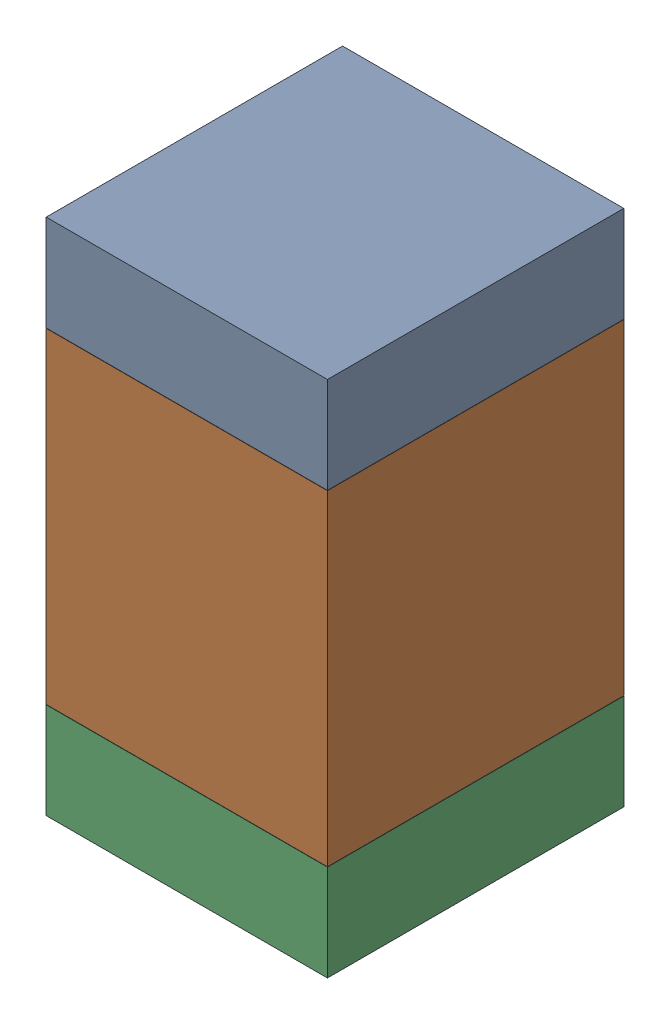
SolidWorks assembly C1, configuration Default. Lengths in mm.
Overall size (0.95 1.75 1).
6 component instances, 2 part files, 0 mates.
Components (placement in the parent):
- 6575495072-1: 6575495072 [Default] at (34.417 41.3525 0) size (0.95 0.32 1)
  - Extruded_6-1: Extruded_6 [Default] at origin size (0.95 0.32 1)
- 6575494912-1: 6575494912 [Default] at (34.417 40.64 0) size (0.95 1.1 1)
  - Extruded_7-1: Extruded_7 [Default] at origin size (0.95 1.1 1)
- 6575495072-2: 6575495072 [Default] at (34.417 39.9275 0) size (0.95 0.32 1)
  - Extruded_6-1: Extruded_6 [Default] at origin size (0.95 0.32 1)
